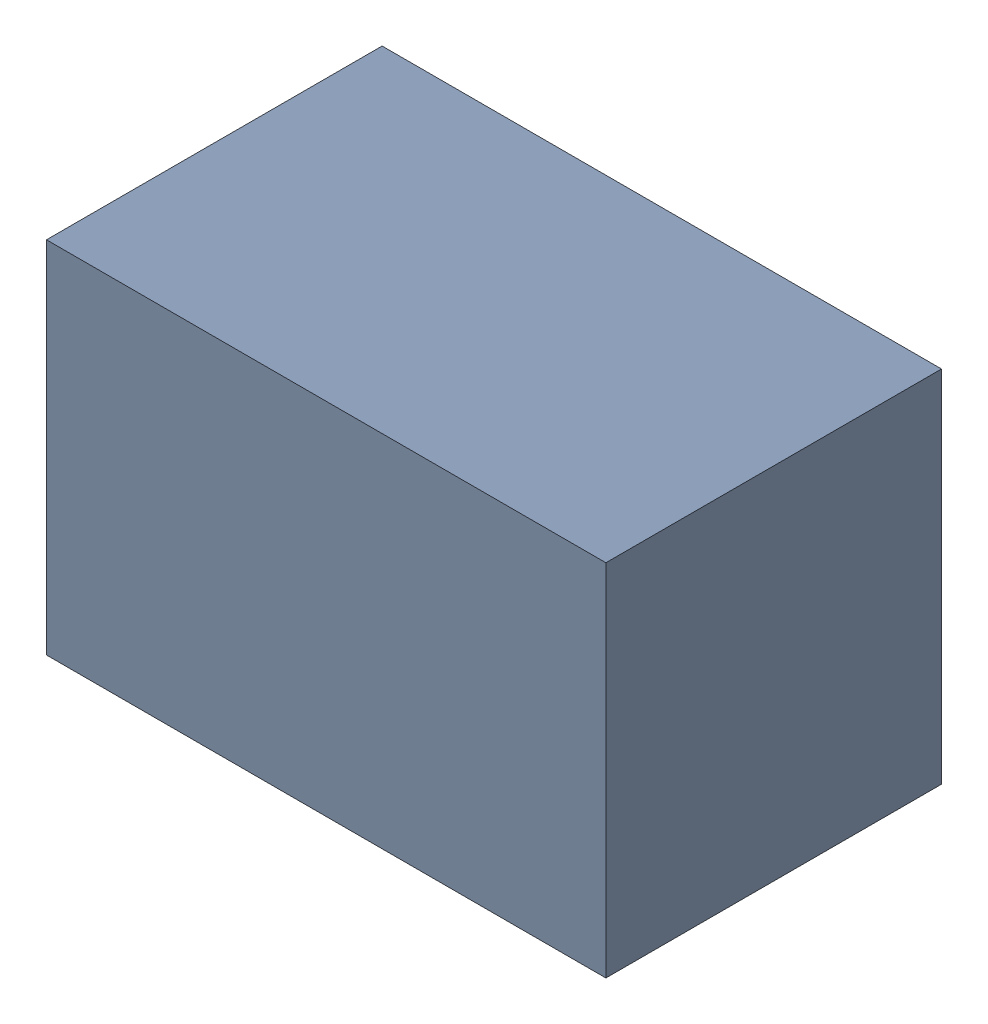
SolidWorks assembly C43, configuration Default. Lengths in mm.
Overall size (2.1 1.35 1.26).
2 component instances, 1 part files, 0 mates.
Components (placement in the parent):
- 407985824-1: 407985824 [Default] at (40.64 57.8104 0.0127) size (2.1 1.35 1.26)
  - Extruded_2-1: Extruded_2 [Default] at origin size (2.1 1.35 1.26)
